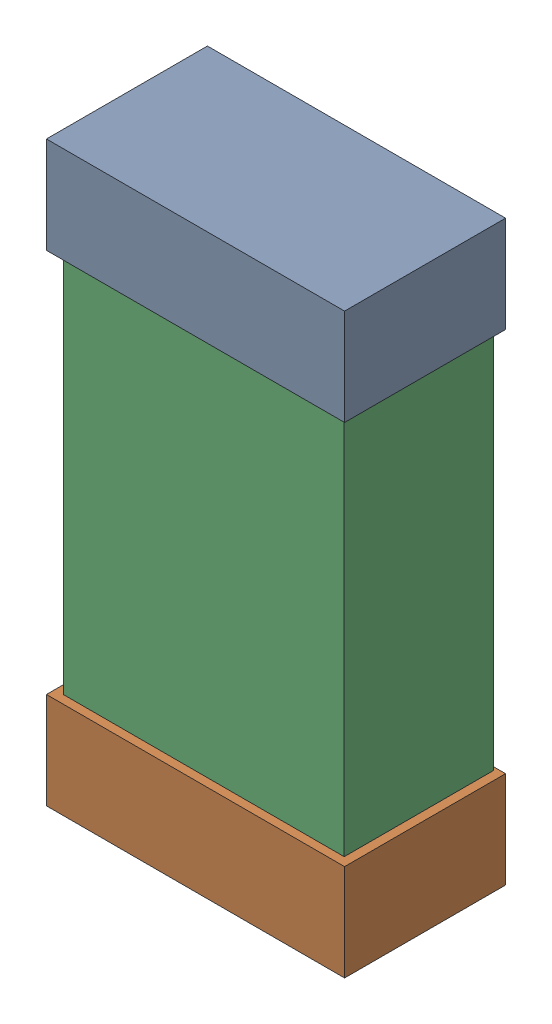
SolidWorks assembly C40, configuration Default. Lengths in mm.
Overall size (0.85 1.65 0.46).
6 component instances, 2 part files, 0 mates.
Components (placement in the parent):
- 432138512_42-1: 432138512_42 [Default] at (21.2405 50.8359 -0.8715) size (0.85 0.28 0.46)
  - Extruded-1: Extruded [Default] at origin size (0.85 0.28 0.46)
- 432138512_43-1: 432138512_43 [Default] at (21.2405 49.4643 -0.8715) size (0.85 0.28 0.46)
  - Extruded-1: Extruded [Default] at origin size (0.85 0.28 0.46)
- 432124816_21-1: 432124816_21 [Default] at (21.2405 50.1501 -0.8615) size (0.8 1.5 0.42)
  - Extruded (1)-1: Extruded (1) [Default] at origin size (0.8 1.5 0.42)
